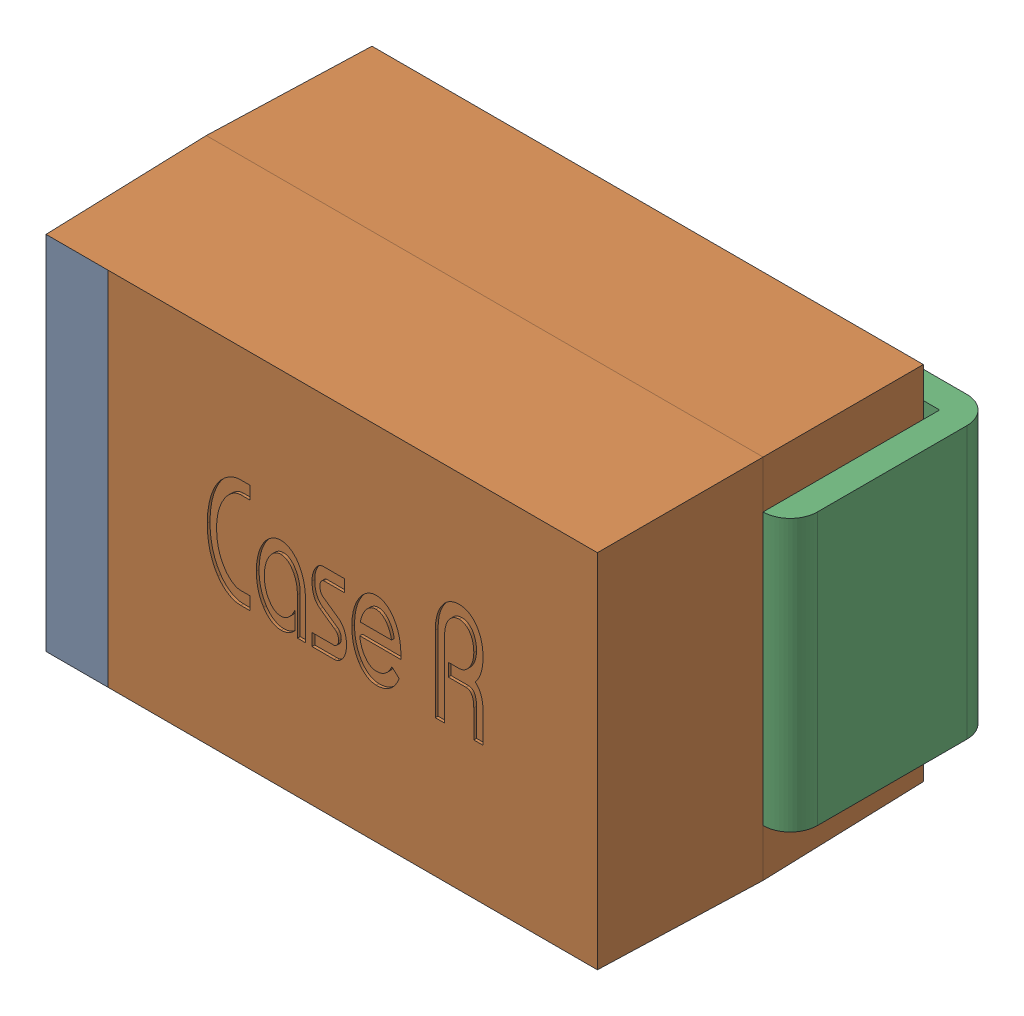
SolidWorks assembly User Library-Arduino Nano 3.0_User Library-Tantalum Capacitor Case R, configuration Default. Lengths in mm.
Overall size (2.25 1.35 1.35).
3 component instances, 2 part files, 6 mates.
Components (placement in the parent):
- User Library-Arduino Nano 3.0_User Library-Tantalum Capacitor Case R_Tantalum case R part1-1: User Library-Arduino Nano 3.0_User Library-Tantalum Capacitor Case R_Tantalum case R part1 [Default] at (-0.9417 -0.5855 -0.8547) size (2.05 1.35 1.2)
- User Library-Arduino Nano 3.0_User Library-Tantalum Capacitor Case R_Tantalum case R part2-1: User Library-Arduino Nano 3.0_User Library-Tantalum Capacitor Case R_Tantalum case R part2 [Default] at (0.7083 0.5895 -0.9047) x (1 0 0) z (0 0 -1) size (0.5 1 0.75)
- User Library-Arduino Nano 3.0_User Library-Tantalum Capacitor Case R_Tantalum case R part2-2: User Library-Arduino Nano 3.0_User Library-Tantalum Capacitor Case R_Tantalum case R part2 [Default] at (-0.5417 -0.4105 -0.9047) x (-1 0 0) z (0 0 -1) size (0.5 1 0.75)
Mates (geometry in assembly coordinates):
- Coincident1: coincident aligned: line of User Library-Arduino Nano 3.0_User Library-Tantalum Capacitor Case R_Tantalum case R part1-1 through (1.1083 0.7645 -0.2547) axis (0 -1 0); line of User Library-Arduino Nano 3.0_User Library-Tantalum Capacitor Case R_Tantalum case R part2-1 through (1.1083 0.5895 -0.2547) axis (0 -1 0)
- Parallel1: parallel anti-aligned: plane of User Library-Arduino Nano 3.0_User Library-Tantalum Capacitor Case R_Tantalum case R part1-1 through (-0.9417 0.7645 -0.8547) normal (0 0 -1); plane of User Library-Arduino Nano 3.0_User Library-Tantalum Capacitor Case R_Tantalum case R part2-1 through (0.7083 -0.4105 -0.9047) normal (0 0 1)
- Coincident3: coincident: moEndPointRef_w of User Library-Arduino Nano 3.0_User Library-Tantalum Capacitor Case R_Tantalum case R part1-1; moEndPointRef_w of User Library-Arduino Nano 3.0_User Library-Tantalum Capacitor Case R_Tantalum case R part2-1
- Coincident4: coincident aligned: line of User Library-Arduino Nano 3.0_User Library-Tantalum Capacitor Case R_Tantalum case R part1-1 through (-0.9417 -0.5855 -0.2547) axis (0 1 0); line of User Library-Arduino Nano 3.0_User Library-Tantalum Capacitor Case R_Tantalum case R part2-2 through (-0.9417 -0.4105 -0.2547) axis (0 1 0)
- Parallel2: parallel anti-aligned: plane of User Library-Arduino Nano 3.0_User Library-Tantalum Capacitor Case R_Tantalum case R part1-1 through (-0.9417 0.7645 -0.8547) normal (0 0 -1); plane of User Library-Arduino Nano 3.0_User Library-Tantalum Capacitor Case R_Tantalum case R part2-2 through (-0.5417 0.5895 -0.9047) normal (0 0 1)
- Coincident6: coincident: moEndPointRef_w of User Library-Arduino Nano 3.0_User Library-Tantalum Capacitor Case R_Tantalum case R part1-1; moEndPointRef_w of User Library-Arduino Nano 3.0_User Library-Tantalum Capacitor Case R_Tantalum case R part2-2
